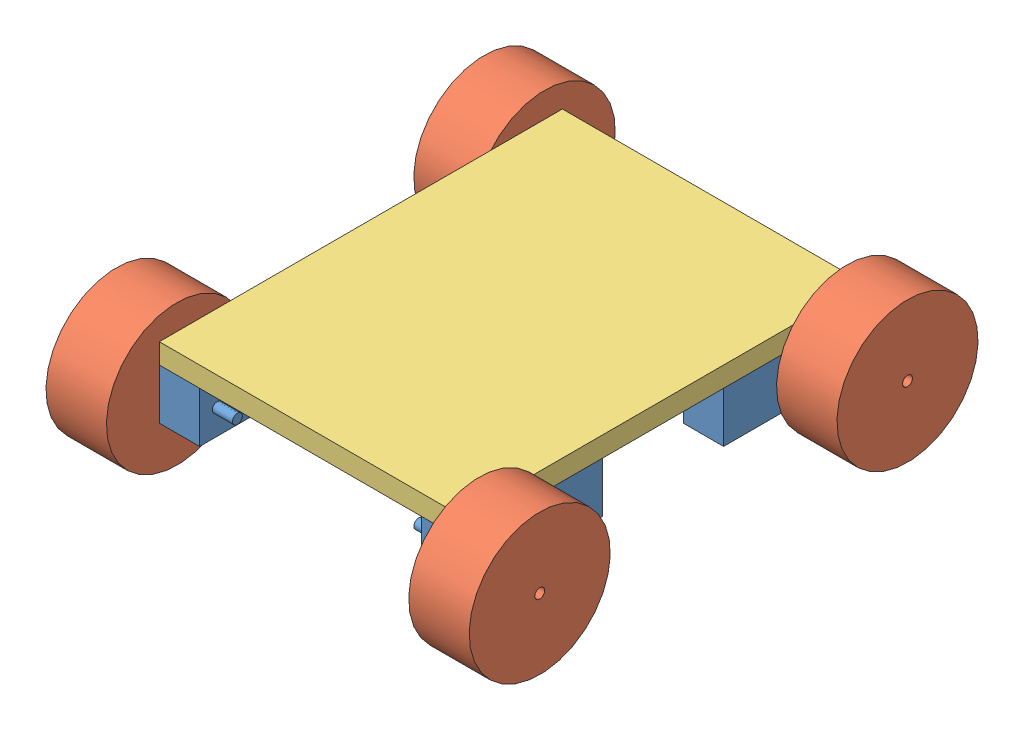
SolidWorks assembly Сборка1, configuration По умолчанию. Lengths in mm.
Overall size (210 74.6 257.1).
9 component instances, 3 part files, 24 mates.
Components (placement in the parent):
- двигатель-1: двигатель [По умолчанию] at origin size (40 25 70)
- колесо-1: колесо [По умолчанию] at (30 12.5 -61.25) x (-1 0 0) z (0 0.997679 0.068098) size (30 70 70)
- двигатель-2: двигатель [По умолчанию] at (-130 0 0) size (40 25 70)
- колесо-2: колесо [По умолчанию] at (-150 12.5 -61.25) x (-1 0 0) z (0 0.997679 0.068098) size (30 70 70)
- колесо-3: колесо [По умолчанию] at (-150 12.5 121.25) x (-1 0 0) z (0 0.997679 0.068098) size (30 70 70)
- двигатель-3: двигатель [По умолчанию] at (-150 0 60) x (-1 0 0) z (0 0 -1) size (40 25 70)
- колесо-4: колесо [По умолчанию] at (30 12.5 121.25) x (-1 0 0) z (0 0.997679 0.068098) size (30 70 70)
- двигатель-4: двигатель [По умолчанию] at (-20 0 60) x (-1 0 0) z (0 0 -1) size (40 25 70)
- доска-1: доска [По умолчанию] at (-150 25 130) size (150 10 200)
Mates (geometry in assembly coordinates):
- Заблокировать1: lock: unknown of двигатель-1; unknown of колесо-1
- Совпадение3: coincident anti-aligned: circle of двигатель-2; circle of колесо-2
- Совпадение7: coincident aligned: line of двигатель-1 through (0 25 -70) axis (-1 0 0); line of двигатель-2 through (-130 25 -70) axis (-1 0 0)
- Совпадение8: coincident aligned: line of двигатель-1 through (-20 25 0) axis (1 0 0); line of двигатель-2 through (-150 25 0) axis (1 0 0)
- Заблокировать3: lock: unknown of двигатель-2; unknown of колесо-2
- Заблокировать4: lock: unknown of двигатель-2; unknown of колесо-2
- Параллельность2: parallel anti-aligned: line of двигатель-2 through (-150 25 0) axis (1 0 0); line of двигатель-3 through (-130 25 60) axis (-1 0 0)
- Совпадение12: coincident aligned: plane of двигатель-2 through (-130 0 0) normal (0 -1 0); plane of двигатель-3 through (-150 0 60) normal (0 -1 0)
- Совпадение13: coincident aligned: plane of двигатель-2 through (-130 25 0) normal (1 0 0); plane of двигатель-3 through (-130 25 60) normal (1 0 0)
- Совпадение15: coincident anti-aligned: circle of колесо-3; circle of двигатель-3
- Заблокировать5: lock: unknown of колесо-3; unknown of двигатель-3
- Параллельность4: parallel anti-aligned: line of двигатель-3 through (-130 25 130) axis (0 0 -1); line of двигатель-4 through (-20 25 60) axis (0 0 1)
- Параллельность5: parallel anti-aligned: line of двигатель-1 through (-20 25 0) axis (1 0 0); line of двигатель-4 through (0 25 60) axis (-1 0 0)
- Совпадение18: coincident aligned: plane of двигатель-1 through (0 25 0) normal (0 1 0); plane of двигатель-4 through (-20 25 60) normal (0 1 0)
- Совпадение19: coincident aligned: plane of двигатель-3 through (-150 25 130) normal (0 0 1); plane of двигатель-4 through (-20 25 130) normal (0 0 1)
- Совпадение20: coincident aligned: plane of двигатель-1 through (-20 25 0) normal (-1 0 0); plane of двигатель-4 through (-20 25 60) normal (-1 0 0)
- Совпадение21: coincident aligned: circle of колесо-4; circle of двигатель-4
- Заблокировать6: lock: unknown of колесо-4; unknown of двигатель-4
- Заблокировать7: lock: unknown of колесо-4; unknown of двигатель-4
- Расстояние2: distance = 200 mm anti-aligned: plane of двигатель-3 through (-150 25 130) normal (0 0 1); plane of двигатель-2 through (-130 25 -70) normal (0 0 -1)
- Расстояние3: distance = 150 mm anti-aligned: plane of двигатель-2 through (-150 25 0) normal (-1 0 0); plane of двигатель-1 through (0 25 0) normal (1 0 0)
- Совпадение26: coincident aligned: line of двигатель-3 through (-150 25 130) axis (1 0 0); line of доска-1 through (-227.7009 25 130) axis (1 0 0)
- Параллельность6: parallel aligned: line of двигатель-1 through (0 0 0) axis (0 0 -1); line of доска-1 through (-77.7009 25 130) axis (0 0 -1)
- Совпадение28: coincident aligned: plane of двигатель-4 through (0 25 60) normal (1 0 0); plane of доска-1 through (0 35 130) normal (1 0 0)
